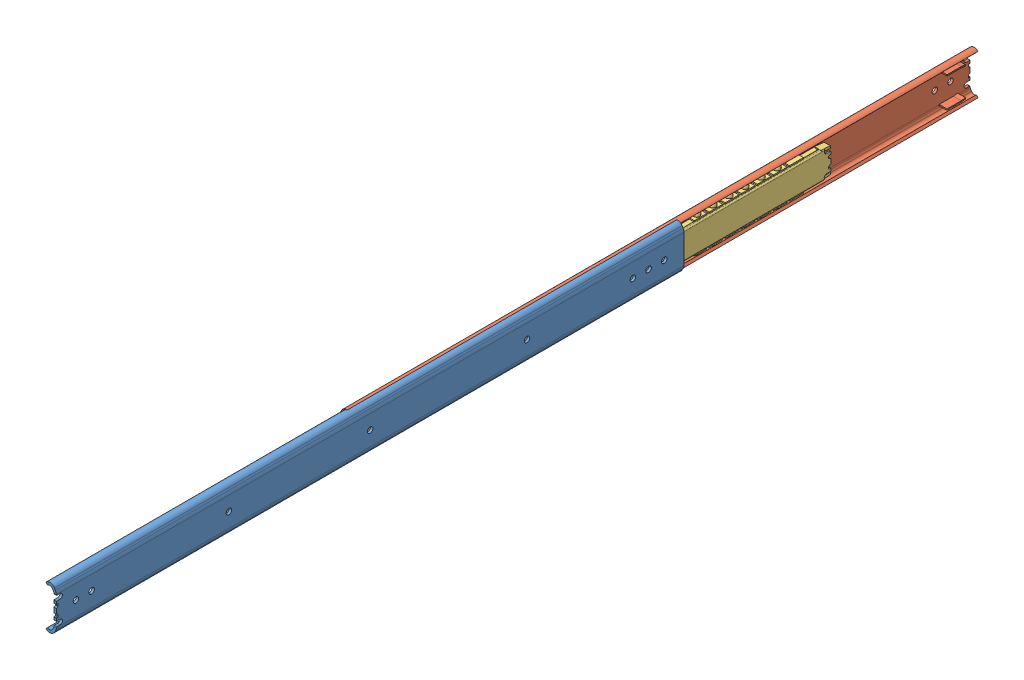
SolidWorks assembly 21-7-3557, configuration Default. Lengths in mm.
Overall size (11.5 35.3 749.17).
4 component instances, 3 part files, 9 mates.
Components (placement in the parent):
- 21-7-3557_01-1: 21-7-3557_01 [Default] at origin size (8.5 35.3 508)
- 21-7-3557_03-1: 21-7-3557_03 [Default] at (7.6 0 281.0336) size (8.5 35.3 508)
- 21-7-3557_02-2: 21-7-3557_02 [Default] at (7.6 0 136.0933) size (7.57 31 250)
- 21-7-3557_02-3: 21-7-3557_02 [Default] at (7.6 0 120.7933) x (1 0 0) z (0 0 -1) size (7.57 31 250)
Mates (geometry in assembly coordinates):
- Coincidente3: coincident aligned: plane of 21-7-3557_02-2 through (-2 10 -113.5567) normal (1 0 0); plane of 21-7-3557_02-3 through (-2 -10 370.4433) normal (1 0 0)
- Coincidente4: coincident anti-aligned: plane of 21-7-3557_02-2 through (-139.177 -15.5 128.4433) normal (0 0 1); plane of 21-7-3557_02-3 through (-139.177 15.5 128.4433) normal (0 0 -1)
- Concêntrico1: concentric anti-aligned: cylinder of 21-7-3557_02-2 through (-6.25 13 -113.5567) axis (0 0 1) radius 2.8284; cylinder of 21-7-3557_02-3 through (-6.25 13 370.4433) axis (0 0 -1) radius 2.8284
- Coincidente8: coincident aligned: plane of 21-7-3557_01-1 through (-2 12.5 494.4) normal (0 1 0); plane of 21-7-3557_02-3 through (-8.5 12.5 356.8433) normal (0 1 0)
- Coincidente9: coincident anti-aligned: plane of 21-7-3557_01-1 through (-2 11.931 508) normal (-1 0 0); plane of 21-7-3557_02-3 through (-2 -10 370.4433) normal (1 0 0)
- DistânciaLimite3: limit distance = 126.0567 mm anti-aligned: plane of 21-7-3557_01-1 through (-2 12.5 482.9) normal (0 0 -1); plane of 21-7-3557_02-3 through (-8 -11 356.8433) normal (0 0 1)
- Coincidente11: coincident aligned: plane of 21-7-3557_03-1 through (-9.5 12.5 -227.5664) normal (0 1 0); plane of 21-7-3557_02-2 through (-8.5 12.5 -99.9567) normal (0 1 0)
- Coincidente12: coincident aligned: plane of 21-7-3557_03-1 through (-3.1602 12.5 -231.0664) normal (1 0 0); plane of 21-7-3557_02-2 through (-3.1602 12.5 -99.9567) normal (1 0 0)
- DistânciaLimite4: limit distance = 116.1097 mm anti-aligned: plane of 21-7-3557_03-1 through (-9.5 12.5 -216.0664) normal (0 0 1); plane of 21-7-3557_02-2 through (-8 11 -99.9567) normal (0 0 -1)
